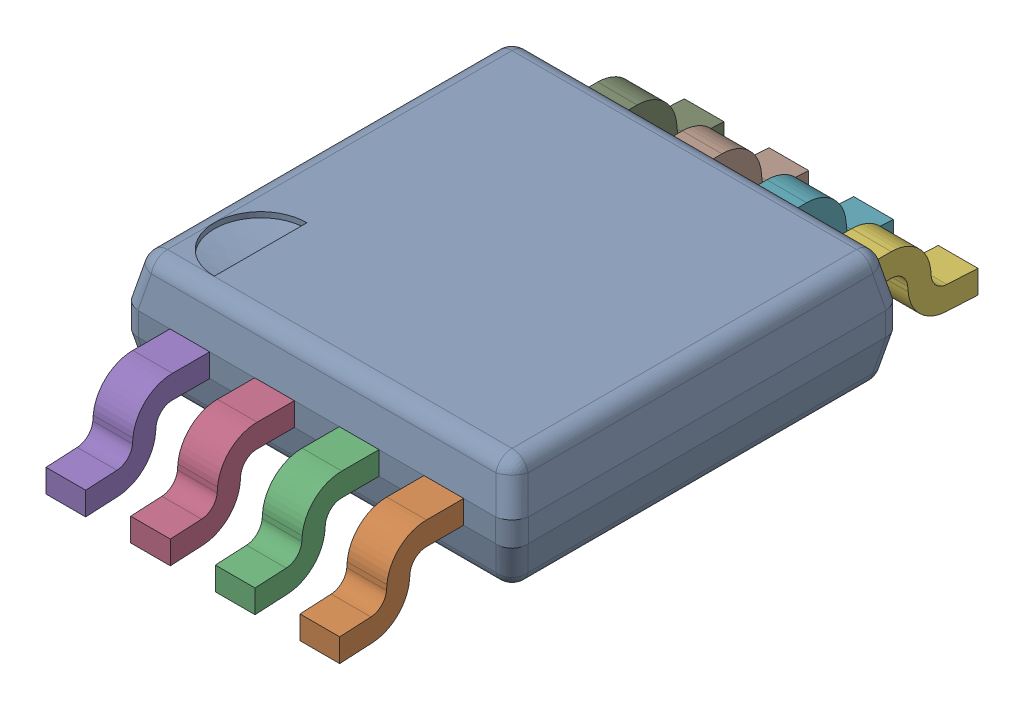
SolidWorks assembly MUY08A_ASM, configuration Default. Lengths in mm.
Overall size (3 0.97 4.9).
10 component instances, 3 part files, 0 mates.
Components (placement in the parent):
- BODY_MUY08A-1: BODY_MUY08A [Default] at origin size (3 0.86 3)
- LEAD_MUY08A-1: LEAD_MUY08A [Default] at (0.9754 -0.3683 1.9177) size (0.31 0.62 0.95)
- LEAD_MUY08A-2: LEAD_MUY08A [Default] at (0.3251 -0.3683 1.9177) size (0.31 0.62 0.95)
- LEAD_MUY08A-3: LEAD_MUY08A [Default] at (-0.3251 -0.3683 1.9177) size (0.31 0.62 0.95)
- LEAD_MUY08A-4: LEAD_MUY08A [Default] at (-0.9754 -0.3683 1.9177) size (0.31 0.62 0.95)
- LEAD_MUY08A-5: LEAD_MUY08A [Default] at (0.9754 -0.3683 -1.9177) x (-1 0 0) z (0 0 -1) size (0.31 0.62 0.95)
- LEAD_MUY08A-6: LEAD_MUY08A [Default] at (0.3251 -0.3683 -1.9177) x (-1 0 0) z (0 0 -1) size (0.31 0.62 0.95)
- LEAD_MUY08A-7: LEAD_MUY08A [Default] at (-0.3251 -0.3683 -1.9177) x (-1 0 0) z (0 0 -1) size (0.31 0.62 0.95)
- LEAD_MUY08A-8: LEAD_MUY08A [Default] at (-0.9754 -0.3683 -1.9177) x (-1 0 0) z (0 0 -1) size (0.31 0.62 0.95)
- EXP_PAD_MUY08A-1: EXP_PAD_MUY08A [Default] at (0 -0.3429 0) size (2.21 0.3 1.73)
